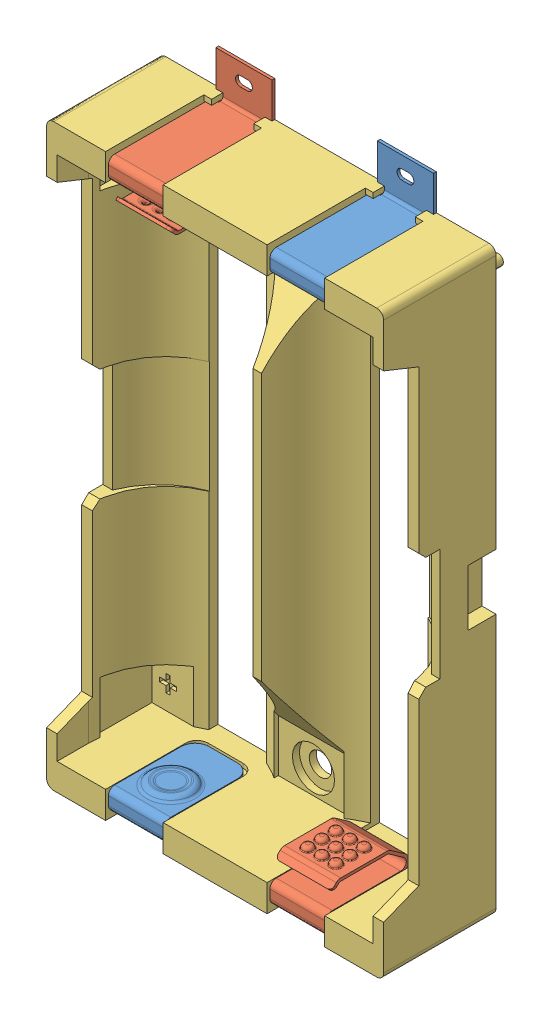
SolidWorks assembly Hold_21700-2p_smd, configuration Default. Lengths in mm.
Overall size (48 92.64 17.3).
5 component instances, 3 part files, 0 mates.
Components (placement in the parent):
- Hold_21700_Con_smd_p-1: Hold_21700_Con_smd_p [Default] at (-11.5 -40 0.8) size (8 9.53 15.7)
- Hold_21700_Con_smd_m-1: Hold_21700_Con_smd_m [Default] at (-11.5 40 0.8) x (-1 0 0) z (0 0 1) size (8 12.94 15.7)
- Hold_21700-2p_smd-1: Hold_21700-2p_smd [Default] at origin size (48 82.5 17.3)
- Hold_21700_Con_smd_p-2: Hold_21700_Con_smd_p [Default] at (11.5 40 0.8) x (-1 0 0) z (0 0 1) size (8 9.53 15.7)
- Hold_21700_Con_smd_m-2: Hold_21700_Con_smd_m [Default] at (11.5 -40 0.8) size (8 12.94 15.7)
